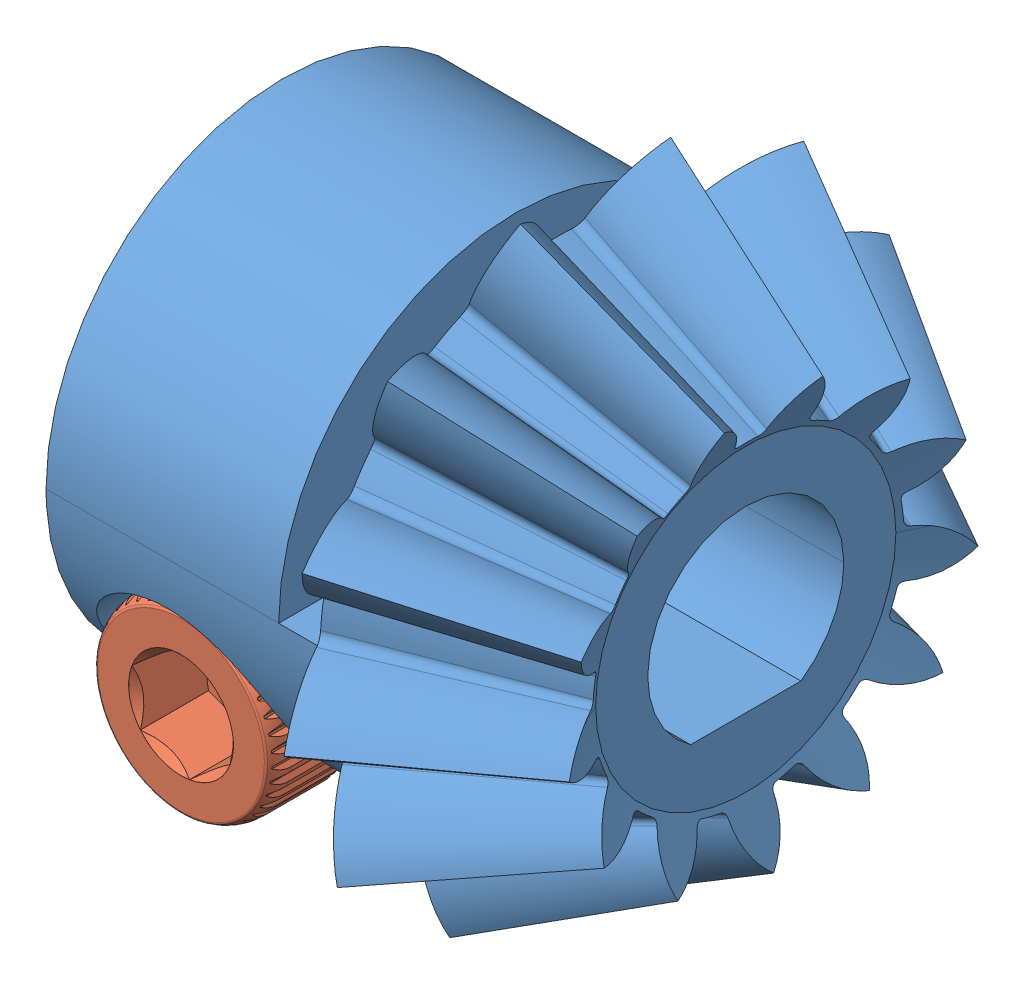
SolidWorks assembly 615458 assembly.STEP, configuration Default. Lengths in mm.
Overall size (15.16 19.24 19.22).
2 component instances, 2 part files, 0 mates.
Components (placement in the parent):
- 615458.STEP-1: 615458.STEP [Default] at (-61.4441 5.8673 28.8984) size (15.1 19.24 19.22)
- 632110_90128A121.STEP-1: 632110_90128A121.STEP [Default] at (-66.148 1.368 -6.0266) x (-0.354662 -0.934995 0) z (0 0 -1) size (5.61 5.61 13.03)
